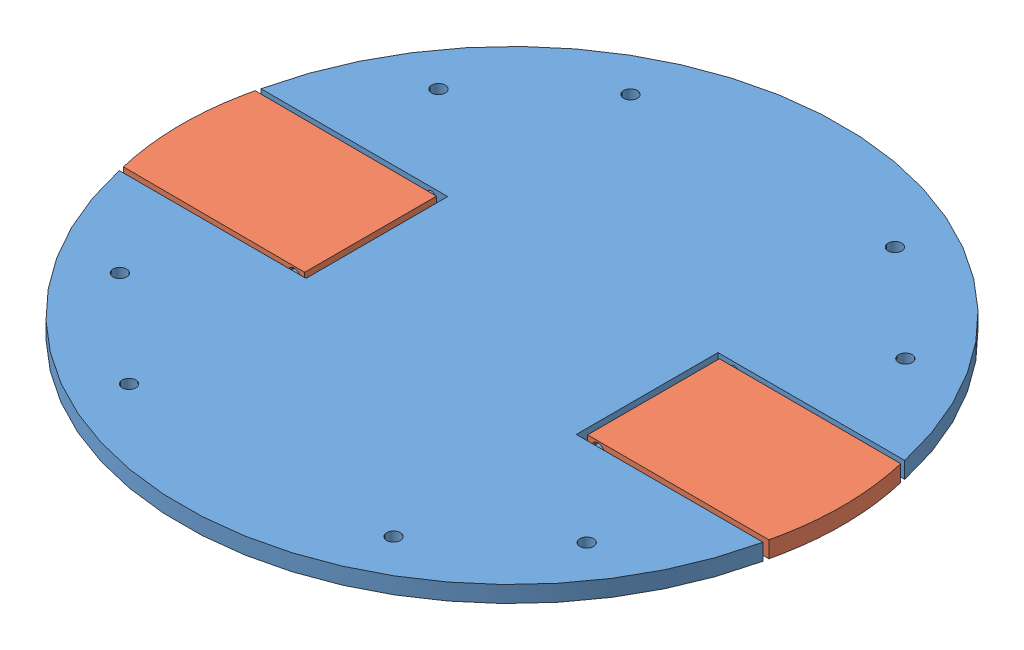
SolidWorks assembly BasewithFlap, configuration Default. Lengths in mm.
Overall size (120.21 3.17 120).
3 component instances, 2 part files, 4 mates.
Components (placement in the parent):
- Bottom Plate-1: Bottom Plate [Default] at origin size (117.19 3 120)
- Flap-1: Flap [Default] at (-25.0942 2.9903 -11.9413) x (0 0 1) z (0.999992 -0.003887 0) size (24 3 34.4)
- Flap-2: Flap [Default] at (25.102 3.0033 11.9422) x (0 0 -1) z (-0.999999 0.001335 0) size (24 3 34.4)
Mates (geometry in assembly coordinates):
- Concentric8: concentric aligned: cylinder of Bottom Plate-1 through (-27.6 1.5 -7.9) axis (0 0 -1) radius 0.9; cylinder of Flap-1 through (-27.6 1.5 -4.9413) axis (0 0 -1) radius 1.2
- Concentric9: concentric aligned: cylinder of Bottom Plate-1 through (-27.6 1.5 7.9) axis (0 0 1) radius 0.9; cylinder of Flap-1 through (-27.6 1.5 5.0587) axis (0 0 1) radius 1.2
- Concentric10: concentric aligned: cylinder of Bottom Plate-1 through (27.6 1.5 -7.9) axis (0 0 -1) radius 0.9; cylinder of Flap-2 through (27.6 1.5 -5.0578) axis (0 0 -1) radius 1.2
- Concentric11: concentric aligned: cylinder of Bottom Plate-1 through (27.6 1.5 7.9) axis (0 0 1) radius 0.9; cylinder of Flap-2 through (27.6 1.5 4.9422) axis (0 0 1) radius 1.2
